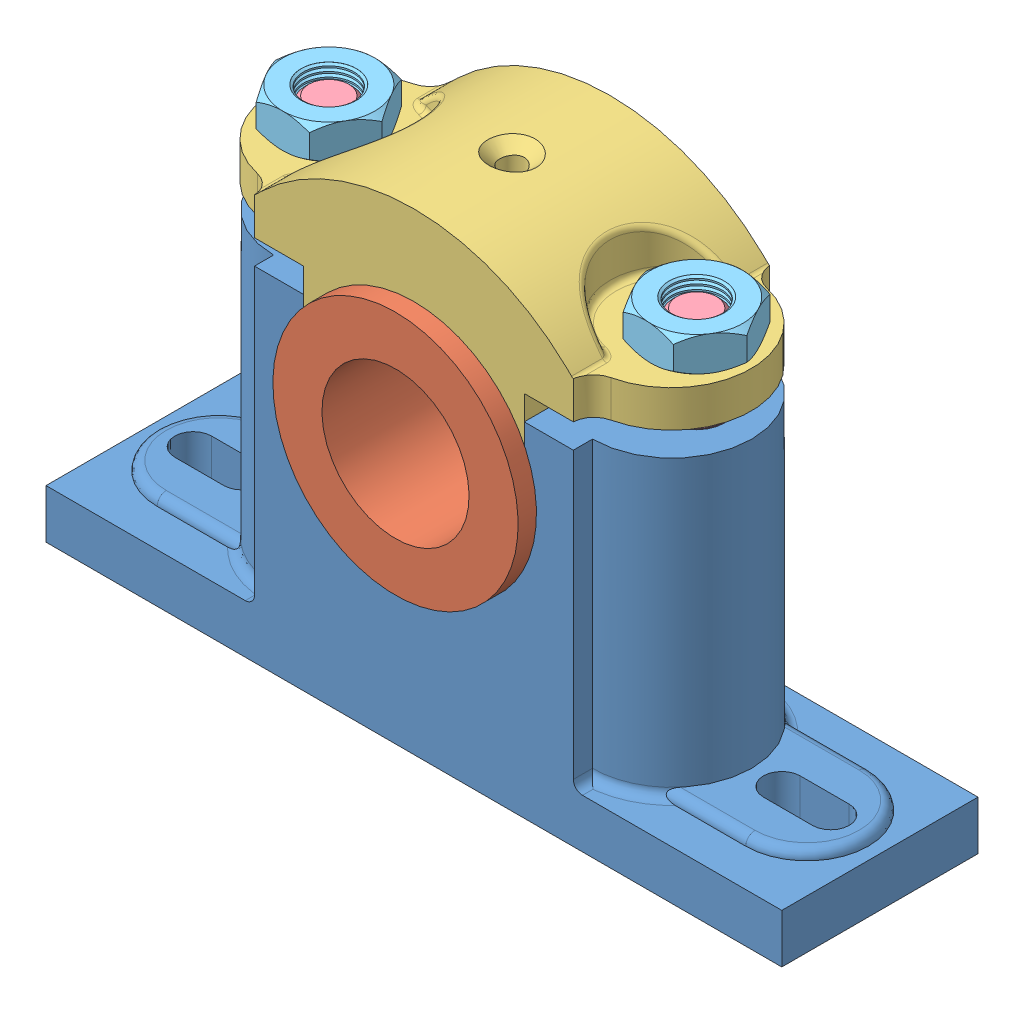
SolidWorks assembly Assem2, configuration Default. Lengths in mm.
Overall size (190.5 122.4 60.32).
7 component instances, 5 part files, 15 mates.
Components (placement in the parent):
- Pedestal Bearing-Base-1: Pedestal Bearing-Base [Default] at origin size (190.5 88.9 50.8)
- Pedestal Bearing Bushing-1: Pedestal Bearing Bushing [Default] at (0 57.15 0) x (0 0 -1) z (-0.701361 0.712807 0) size (60.32 63.5 63.5)
- Pedestal Bearing-Cap-1: Pedestal Bearing-Cap [Default] at (28.575 57.15 25.4) size (123.82 52.55 50.8)
- heavy hex bolt_ai-2: heavy hex bolt_ai [HHBOLT 0.5000-13x4x1-S] at (47.625 -12.4206 -0.1912) x (0 1 0) z (0.5 0 0.866025) size (110.85 25.66 22.23)
- heavy hex bolt_ai-3: heavy hex bolt_ai [HHBOLT 0.5000-13x4x1-S] at (-47.625 -12.4206 -0.1912) x (0 1 0) z (0.5 0 0.866025) size (110.85 25.66 22.23)
- heavy hex jam nut_ai-1: heavy hex jam nut_ai [HHJNUT 0.5625-18-D-S] at (47.625 100.9396 -0.1912) x (-0.837169 0 -0.546944) z (0 1 0) size (23.83 27.51 8.86)
- heavy hex jam nut_ai-2: heavy hex jam nut_ai [HHJNUT 0.5625-18-D-S] at (-47.625 92.075 -0.1912) x (0.866025 0 -0.5) z (0 -1 0) size (23.83 27.51 8.86)
Mates (geometry in assembly coordinates):
- Concentric1: concentric anti-aligned: cylinder of Pedestal Bearing-Base-1 through (0 57.15 106.2223) axis (0 0 -1) radius 23.8125; cylinder of Pedestal Bearing Bushing-1 through (0 57.15 30.1625) axis (0 0 1) radius 23.8125
- Coincident1: coincident anti-aligned: plane of Pedestal Bearing-Base-1 through (95.25 -12.7 25.4) normal (0 0 1); plane of Pedestal Bearing Bushing-1 through (-16.9737 40.4489 25.4) normal (0 0 -1)
- Coincident2: coincident anti-aligned: plane of Pedestal Bearing-Cap-1 through (-28.575 57.15 -25.4) normal (0 -1 0); plane of Pedestal Bearing-Base-1 through (-23.8125 57.15 106.2223) normal (0 1 0)
- Coincident3: coincident anti-aligned: plane of Pedestal Bearing-Base-1 through (-28.575 76.2 -25.4) normal (1 0 0); plane of Pedestal Bearing-Cap-1 through (-28.575 82.55 -25.4) normal (-1 0 0)
- Coincident4: coincident aligned: plane of Pedestal Bearing-Base-1 through (95.25 -12.7 25.4) normal (0 0 1); plane of Pedestal Bearing-Cap-1 through (0 52.5466 25.4) normal (0 0 1)
- Coincident9: coincident anti-aligned: plane of Pedestal Bearing-Base-1 through (0 -3.175 0) normal (0 -1 0); plane of heavy hex bolt_ai-2 through (36.5125 -3.175 6.2246) normal (0 1 0)
- Concentric4: concentric aligned: cylinder of Pedestal Bearing-Base-1 through (47.625 76.2 -0.1912) axis (0 -1 0) radius 7.1437; cylinder of heavy hex bolt_ai-2 through (47.625 -12.4206 -0.1912) axis (0 -1 0) radius 6.35
- Parallel3: parallel anti-aligned: plane of Pedestal Bearing-Base-1 through (35.7188 -3.175 6.6829) normal (0.5 0 -0.866025); plane of heavy hex bolt_ai-2 through (36.5125 -3.175 6.2246) normal (-0.5 0 0.866025)
- Coincident11: coincident anti-aligned: plane of Pedestal Bearing-Base-1 through (0 -3.175 0) normal (0 -1 0); plane of heavy hex bolt_ai-3 through (-58.7375 -3.175 6.2246) normal (0 1 0)
- Concentric5: concentric aligned: cylinder of Pedestal Bearing-Base-1 through (-47.625 76.2 -0.1912) axis (0 -1 0) radius 7.1437; cylinder of heavy hex bolt_ai-3 through (-47.625 -12.4206 -0.1912) axis (0 -1 0) radius 6.35
- Parallel4: parallel anti-aligned: plane of Pedestal Bearing-Base-1 through (-47.625 -3.175 13.557) normal (0.5 0 -0.866025); plane of heavy hex bolt_ai-3 through (-58.7375 -3.175 6.2246) normal (-0.5 0 0.866025)
- Coincident13: coincident anti-aligned: plane of Pedestal Bearing-Cap-1 through (-41.275 92.075 -25.4) normal (0 1 0); plane of heavy hex jam nut_ai-2 through (-40.7473 92.075 11.7214) normal (0 -1 0)
- Concentric6: concentric anti-aligned: circle of heavy hex bolt_ai-3; circle of heavy hex jam nut_ai-2
- Coincident14: coincident: plane of Pedestal Bearing-Cap-1 through (61.9125 92.075 -25.4) normal (0 1 0); plane of heavy hex jam nut_ai-1 through (40.1015 92.075 11.3245) normal (0 -1 0)
- Concentric7: concentric anti-aligned: circle of heavy hex bolt_ai-2; circle of heavy hex jam nut_ai-1
